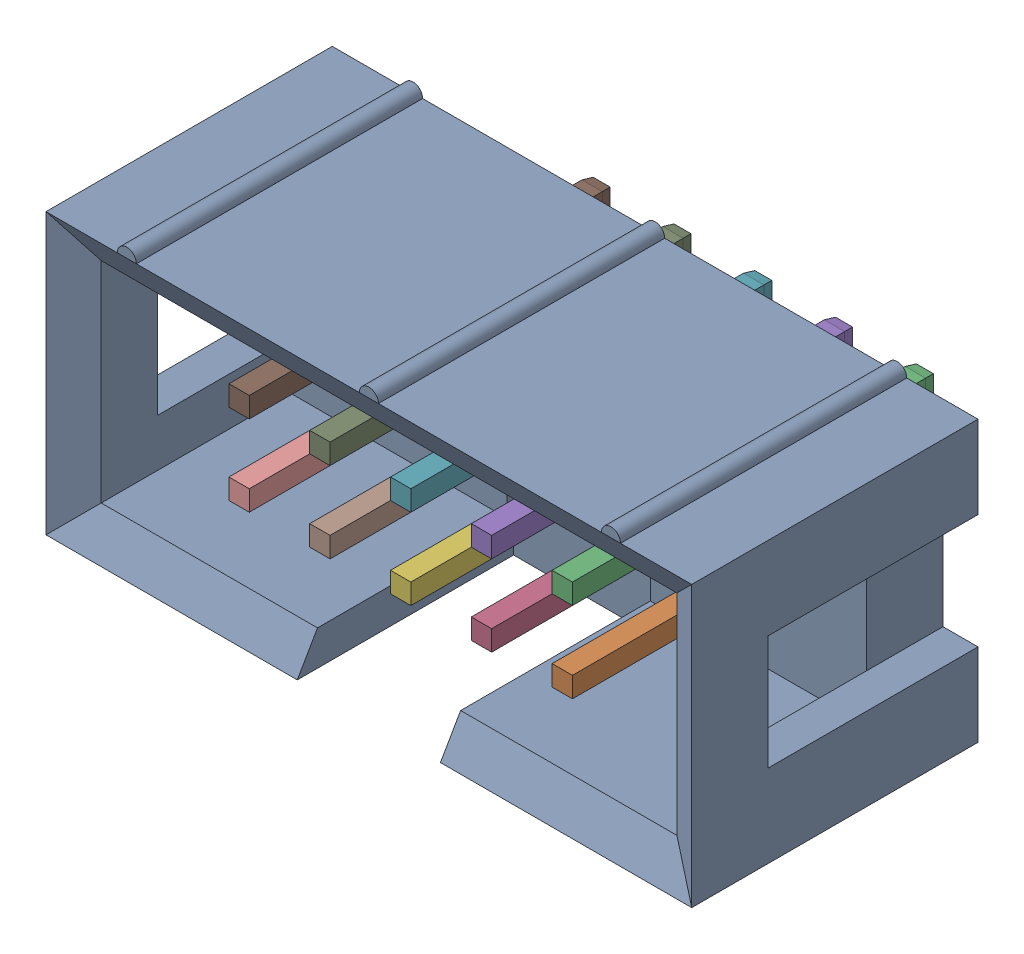
SolidWorks assembly User Library-IDC-10M, configuration ﾃﾞﾌｫﾙﾄ. Lengths in mm.
Overall size (20.3 9.1 12.4).
11 component instances, 2 part files, 0 mates.
Components (placement in the parent):
- IDC-10M_Body___ _________-1: IDC-10M_Body___ _________ [ﾃﾞﾌｫﾙﾄ] at origin size (20.3 9.1 9.3)
- IDC_pin___ _________-1: IDC_pin___ _________ [ﾃﾞﾌｫﾙﾄ] at (5.08 -1.27 -3.1) size (0.64 0.64 11.4)
- IDC_pin___ _________-2: IDC_pin___ _________ [ﾃﾞﾌｫﾙﾄ] at (5.08 1.27 -3.1) size (0.64 0.64 11.4)
- IDC_pin___ _________-3: IDC_pin___ _________ [ﾃﾞﾌｫﾙﾄ] at (2.54 -1.27 -3.1) size (0.64 0.64 11.4)
- IDC_pin___ _________-4: IDC_pin___ _________ [ﾃﾞﾌｫﾙﾄ] at (2.54 1.27 -3.1) size (0.64 0.64 11.4)
- IDC_pin___ _________-5: IDC_pin___ _________ [ﾃﾞﾌｫﾙﾄ] at (0 -1.27 -3.1) size (0.64 0.64 11.4)
- IDC_pin___ _________-6: IDC_pin___ _________ [ﾃﾞﾌｫﾙﾄ] at (0 1.27 -3.1) size (0.64 0.64 11.4)
- IDC_pin___ _________-7: IDC_pin___ _________ [ﾃﾞﾌｫﾙﾄ] at (-2.54 -1.27 -3.1) size (0.64 0.64 11.4)
- IDC_pin___ _________-8: IDC_pin___ _________ [ﾃﾞﾌｫﾙﾄ] at (-2.54 1.27 -3.1) size (0.64 0.64 11.4)
- IDC_pin___ _________-9: IDC_pin___ _________ [ﾃﾞﾌｫﾙﾄ] at (-5.08 -1.27 -3.1) size (0.64 0.64 11.4)
- IDC_pin___ _________-10: IDC_pin___ _________ [ﾃﾞﾌｫﾙﾄ] at (-5.08 1.27 -3.1) size (0.64 0.64 11.4)
